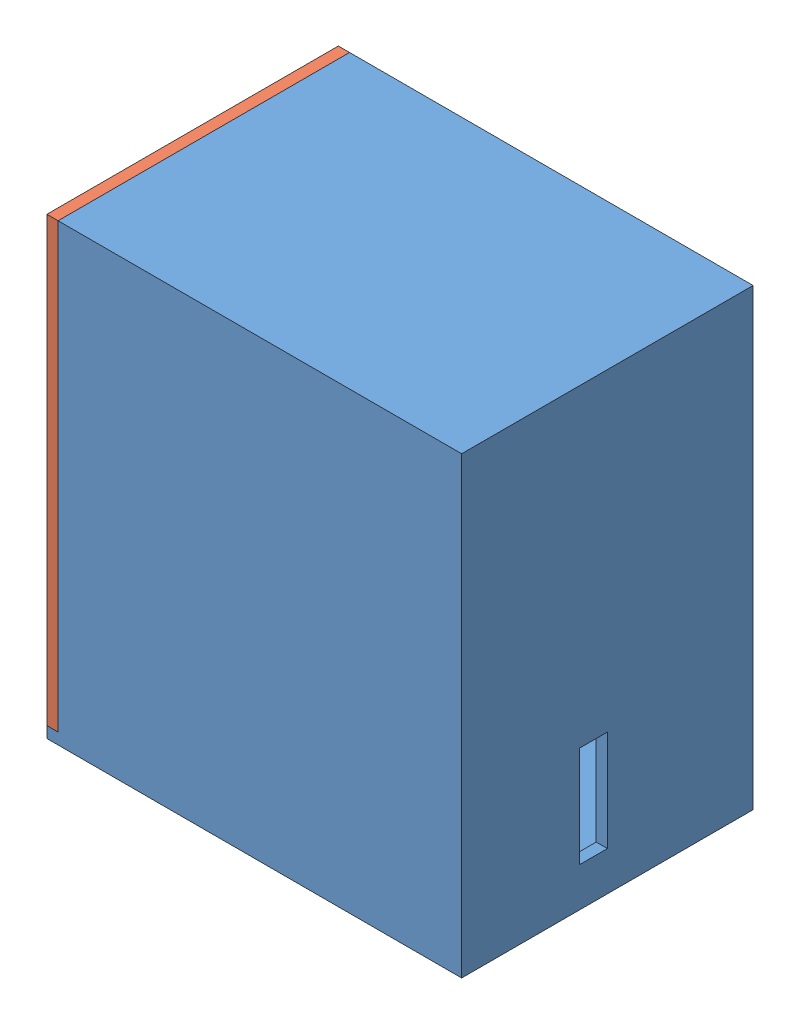
SolidWorks assembly GehauseMitInhalt, configuration Standard. Lengths in mm.
Overall size (74 81 52).
4 component instances, 4 part files, 9 mates.
Components (placement in the parent):
- Teil-1-1: Teil-1 [Standard] at (19.5912 29.1442 99) size (74 81 52)
- nodeMCUboard-2: nodeMCUboard [Standard] at (-31.5614 -23.3571 99) x (1 0 0) z (0 0 -1) (suppressed, hidden)
- Teil-2-Frontplate.STL-2: Teil-2-Frontplate.STL [Standard] at (-59.8555 15.8443 46.5977) x (0 1 0) z (-1 0 0) size (79 52 6)
- Teil-3-deckel.STL-1: Teil-3-deckel.STL [Standard] at (-20.5952 15.0038 47) (suppressed, hidden)
Mates (geometry in assembly coordinates):
- Deckungsgleich7: coincident anti-aligned: plane of Teil-1-1 through (19.5912 29.1442 99) normal (0 0 -1); plane of nodeMCUboard-2 through (-31.5614 -23.3571 99) normal (0 0 1)
- Deckungsgleich13: coincident anti-aligned: plane of Teil-1-1 through (-59.8555 33.3538 101) normal (-1 0 0); plane of Teil-2-Frontplate.STL-2 through (-59.8555 15.8443 46.5977) normal (1 0 0)
- Deckungsgleich18: coincident aligned: plane of Teil-1-1 through (19.5912 35.3538 99) normal (0 1 0); plane of Teil-2-Frontplate.STL-2 through (-61.8555 35.3538 49) normal (0 1 0)
- Deckungsgleich20: coincident aligned: plane of Teil-1-1 through (12.1445 33.3538 49) normal (0 0 -1); plane of Teil-2-Frontplate.STL-2 through (-61.8555 -43.6462 49) normal (0 0 -1)
- Deckungsgleich25: coincident anti-aligned: plane of Teil-1-1 through (10.1445 29.1442 99) normal (-1 0 0); plane of nodeMCUboard-2 through (10.1445 -38.6462 75) normal (1 0 0)
- Deckungsgleich26: coincident anti-aligned: plane of Teil-1-1 through (19.5912 -43.6462 99) normal (0 1 0); plane of nodeMCUboard-2 through (-58.8066 -43.6462 80) normal (0 -1 0)
- Deckungsgleich27: coincident anti-aligned: plane of Teil-1-1 through (12.1445 33.3538 49) normal (0 0 -1); plane of Teil-3-deckel.STL-1 through (-20.5952 15.0038 49) normal (0 0 1)
- Deckungsgleich28: coincident aligned: plane of Teil-1-1 through (19.5912 -45.6462 99) normal (0 -1 0); plane of Teil-3-deckel.STL-1 through (-61.8555 -45.6462 49) normal (0 -1 0)
- Deckungsgleich29: coincident aligned: plane of Teil-2-Frontplate.STL-2 through (-61.8555 15.8443 46.5977) normal (-1 0 0); plane of Teil-3-deckel.STL-1 through (-61.8555 35.3538 49) normal (-1 0 0)
